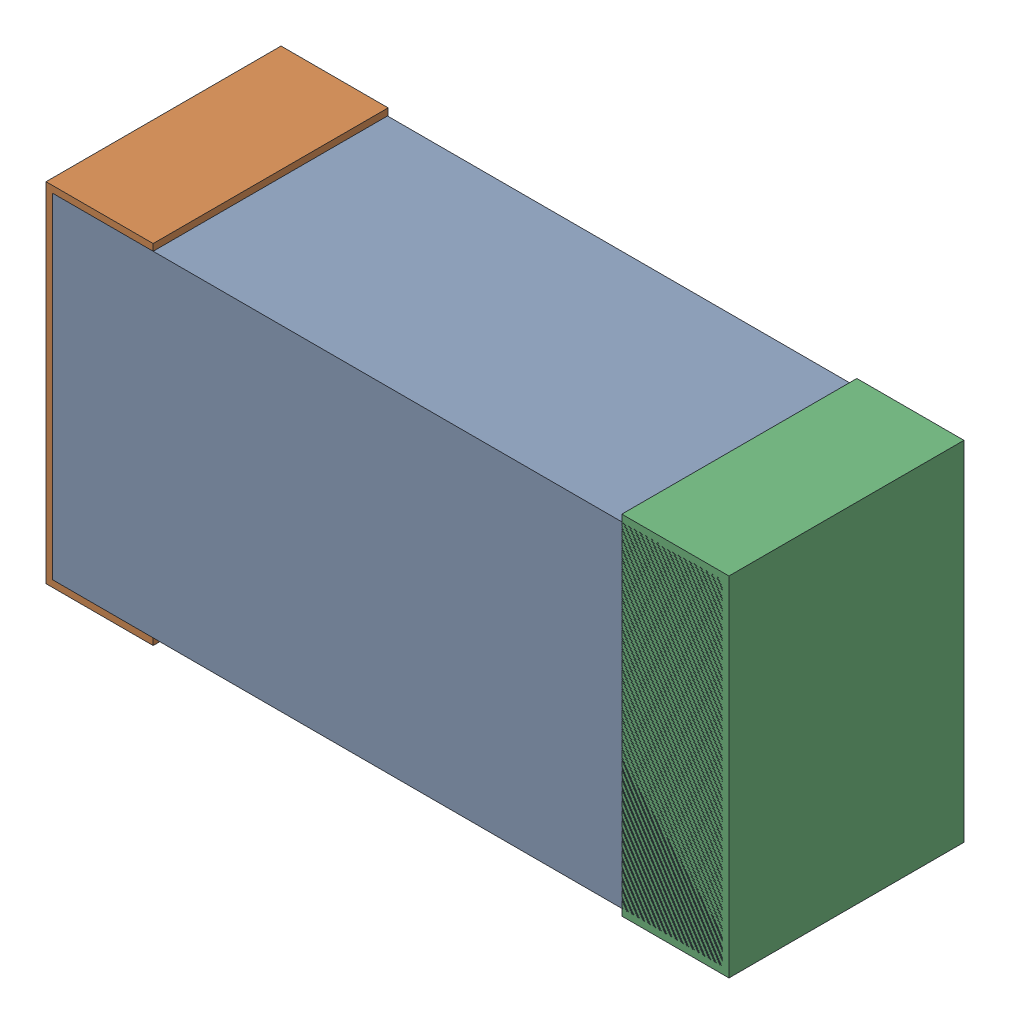
SolidWorks assembly C55, configuration Default. Lengths in mm.
Overall size (1.02 0.52 0.35).
6 component instances, 2 part files, 0 mates.
Components (placement in the parent):
- 870940640-1: 870940640 [Default] at (61.3982 17.1936 -1.9506) size (1 0.5 0.35)
  - Extruded_2-1: Extruded_2 [Default] at origin size (1 0.5 0.35)
- 870940480-1: 870940480 [Default] at (60.9682 17.1936 -1.9516) size (0.16 0.52 0.35)
  - Extruded-1: Extruded [Default] at origin size (0.16 0.52 0.35)
- 870940480-2: 870940480 [Default] at (61.8282 17.1936 -1.9516) size (0.16 0.52 0.35)
  - Extruded-1: Extruded [Default] at origin size (0.16 0.52 0.35)
